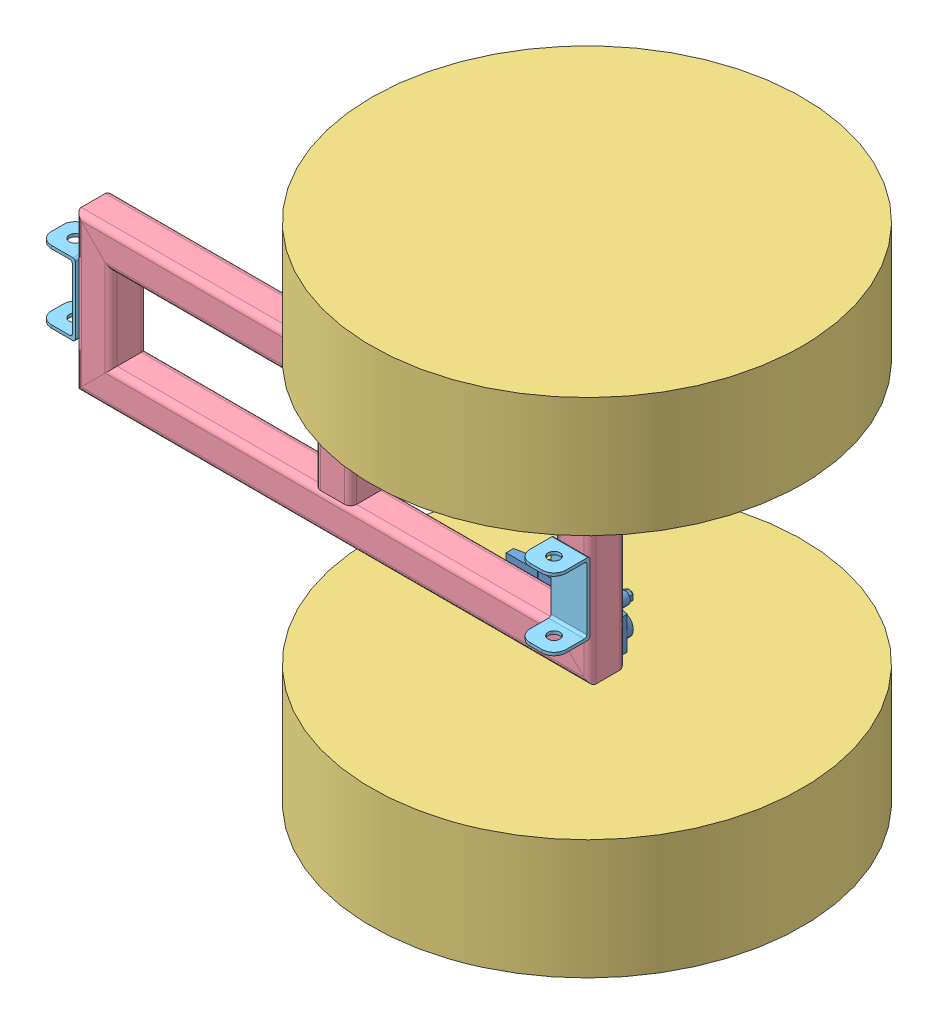
SolidWorks assembly RearSwingArmAssm, configuration Default. Lengths in mm.
Overall size (814.08 533.4 593.11).
8 component instances, 5 part files, 15 mates.
Components (placement in the parent):
- 6359K370-1: 6359K370 [6359K37] at (6.6266 77.7602 464.7109) size (120.65 50.8 53.86)
- 6359K370-2: 6359K370 [6359K37] at (6.6266 -39.7148 464.7109) size (120.65 50.8 53.86)
- 1497K961-shaft-18in-1: 1497K961-shaft-18in [1497K961] at (6.6266 19.3186 439.3109) x (0.999354 0 -0.035933) z (0 1 0) size (25.4 25.4 457.2)
- Wheel-1: Wheel [Default] at (6.6266 -233.9506 439.3109) x (0.36706 0 0.930197) z (0 1 0) size (457.2 457.2 127)
- Wheel-2: Wheel [Default] at (6.6266 299.4494 439.3109) x (1 0 0) z (0 -1 0) size (457.2 457.2 127)
- RearSwingArm2-1: RearSwingArm2 [Default<As Machined>] at (-521.5966 -73.0593 483.7609) size (546.1 165.1 38.1)
- U-BracketInside-1: U-BracketInside [Default] at (-482.9187 51.5664 502.8109) x (0 -1 0) z (1 0 0) size (76.2 38.1 38.1)
- U-BracketInside-2: U-BracketInside [Default] at (73.3016 51.5664 512.9312) x (0 -1 0) z (0 0 -1) size (76.2 38.1 38.1)
Mates (geometry in assembly coordinates):
- Coincident1: coincident anti-aligned: plane of 6359K370-2 through (-53.6984 -57.1773 464.7109) normal (0 0 1); plane of RearSwingArm2-1 through (54.2516 -57.1773 464.7109) normal (0 0 -1)
- Coincident2: coincident aligned: line of 6359K370-2 through (66.9516 -22.2523 464.7109) axis (0 -1 0); line of RearSwingArm2-1 through (66.9516 95.2227 464.7109) axis (0 -1 0)
- Distance1: distance = 0 mm: line of 6359K370-2 through (-53.6984 -57.1773 464.7109) axis (1 0 0); line of RearSwingArm2-1 through (66.9516 -57.1773 464.7109) axis (-1 0 0)
- Coincident6: coincident anti-aligned: plane of 6359K370-1 through (-53.6984 60.2977 464.7109) normal (0 0 1); plane of RearSwingArm2-1 through (-453.7484 95.2227 464.7109) normal (0 0 -1)
- Coincident7: coincident aligned: line of 6359K370-1 through (66.9516 95.2227 464.7109) axis (0 -1 0); line of RearSwingArm2-1 through (66.9516 95.2227 464.7109) axis (0 -1 0)
- Distance2: distance = 0 mm: line of 6359K370-1 through (-53.6984 95.2227 464.7109) axis (1 0 0); line of RearSwingArm2-1 through (-466.4484 95.2227 464.7109) axis (1 0 0)
- Coincident13: coincident anti-aligned: plane of RearSwingArm2-1 through (-472.7984 -44.4773 471.0609) normal (-1 0 0); plane of U-BracketInside-1 through (-472.7984 57.1227 464.7109) normal (1 0 0)
- Coincident17: coincident aligned: line of RearSwingArm2-1 through (-472.7984 19.0227 496.4609) axis (0 0 -1); line of U-BracketInside-1 through (-472.7984 19.0227 502.8109) axis (0 0 -1)
- Coincident18: coincident anti-aligned: line of RearSwingArm2-1 through (-472.7984 101.5727 483.7609) axis (0 -1 0); line of U-BracketInside-1 through (-472.7984 -16.5373 483.7609) axis (0 1 0)
- Concentric1: concentric anti-aligned: cylinder of 6359K370-1 through (6.6266 161.927 439.3109) axis (0 -1 0) radius 12.7; circle of 1497K961-shaft-18in-1
- Concentric5: concentric anti-aligned: circle of 1497K961-shaft-18in-1; circle of Wheel-1
- Concentric6: concentric anti-aligned: circle of 1497K961-shaft-18in-1; circle of Wheel-2
- Coincident22: coincident anti-aligned: plane of RearSwingArm2-1 through (41.5516 82.5227 502.8109) normal (0 0 1); plane of U-BracketInside-2 through (35.2016 57.1227 502.8109) normal (0 0 -1)
- Coincident23: coincident aligned: line of RearSwingArm2-1 through (66.9516 19.0227 502.8109) axis (-1 0 0); line of U-BracketInside-2 through (73.3016 19.0227 502.8109) axis (-1 0 0)
- Coincident24: coincident aligned: line of RearSwingArm2-1 through (54.2516 -44.4773 502.8109) axis (0 1 0); line of U-BracketInside-2 through (54.2516 -16.5373 502.8109) axis (0 1 0)
